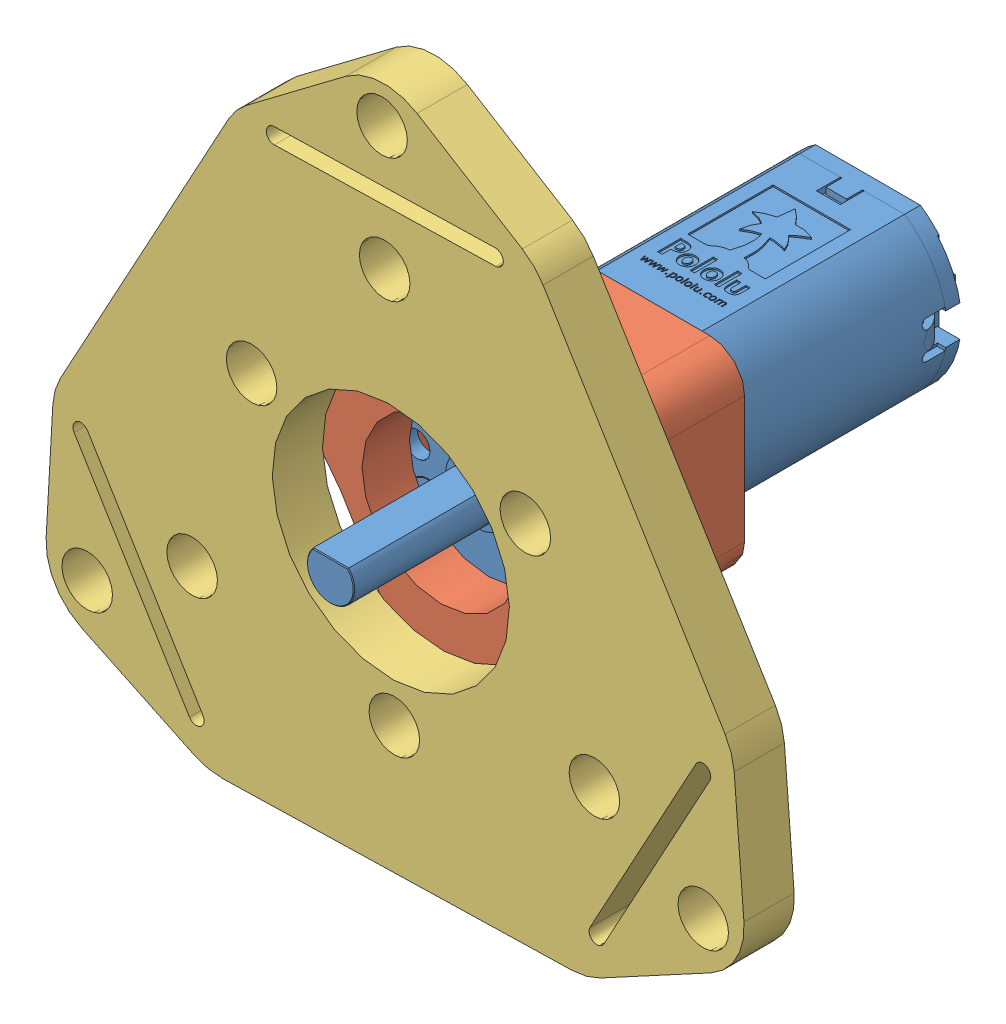
SolidWorks assembly Motor Flange, configuration Default. Lengths in mm.
Overall size (45.21 43.99 35.8).
3 component instances, 3 part files, 6 mates.
Components (placement in the parent):
- micro-metal-gearmotor-1: micro-metal-gearmotor [Default] at origin size (12 10.04 35.8)
- Motor Flange-1: Motor Flange [Default] x (-1 0 0) z (0 0 -1) size (22.63 20.51 12.4)
- Top Acrylic Base-1: Top Acrylic Base [Default] at (-21.9522 -13.3601 12) x (0.999695 0.024698 0) z (0 0 1) size (44.16 42.91 3.17)
Mates (geometry in assembly coordinates):
- InPlace1: in place: plane of micro-metal-gearmotor-1 through (-6 -5 0) normal (0 0 -1); plane of Motor Flange-1 through (0 0 0) normal (0 0 -1); moOrthogonalPlaneRef_w of micro-metal-gearmotor-1 through (-6 -5 0) normal (0 0 -1); plane of Motor Flange-1 through (0 0 0) normal (0 1 0); plane of micro-metal-gearmotor-1 through (-6 -5 0) normal (0 0 -1); plane of Motor Flange-1 through (0 0 0) normal (-1 0 0); plane of micro-metal-gearmotor-1 through (-6 -5 0) normal (0 0 -1); unknown of Motor Flange-1
- Coincident1: coincident aligned: plane of micro-metal-gearmotor-1; plane of Motor Flange-1
- Coincident2: coincident aligned: moOrthogonalPlaneRef_w of micro-metal-gearmotor-1 through (0 0 0) normal (0 1 0); plane of Motor Flange-1 through (0 0 0) normal (0 1 0)
- Coincident3: coincident anti-aligned: moOrthogonalPlaneRef_w of micro-metal-gearmotor-1 through (0 0 0) normal (1 0 0); plane of Motor Flange-1 through (0 0 0) normal (-1 0 0)
- Concentric1: concentric aligned: cylinder of micro-metal-gearmotor-1 through (0 0 13.525) axis (0 0 1) radius 1.5; cylinder of Top Acrylic Base-1 through (0 0 12) axis (0 0 1) radius 7.5
- Distance1: distance = 3 mm anti-aligned: plane of Top Acrylic Base-1 through (-21.9522 -13.3601 12) normal (0 0 -1); plane of micro-metal-gearmotor-1 through (-6 5 9) normal (0 0 1)
